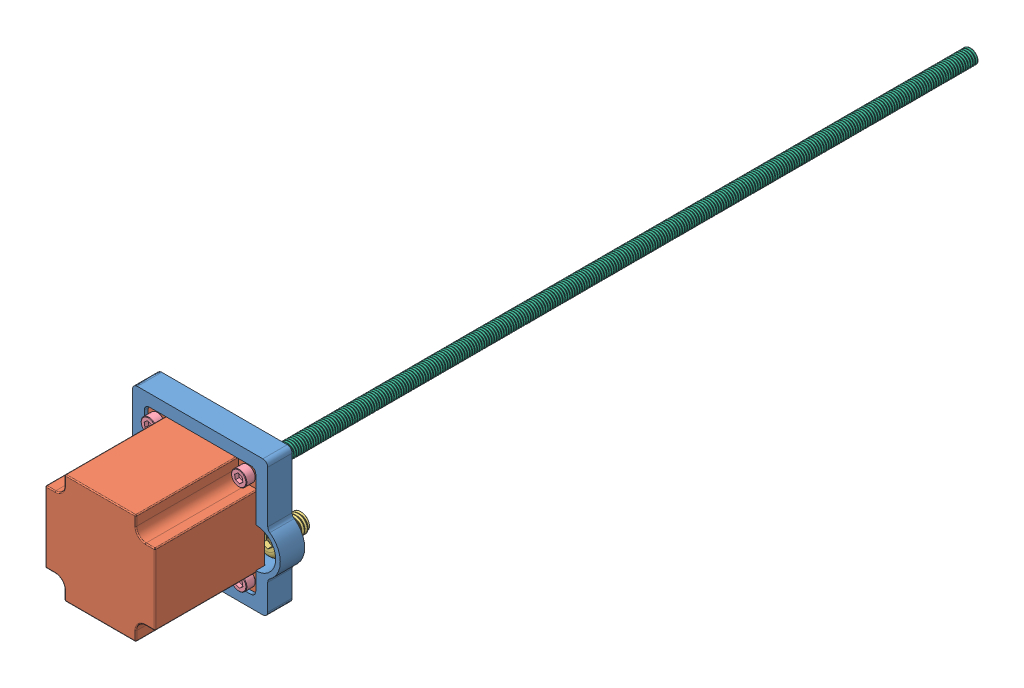
SolidWorks assembly motor_assembly, configuration Default. Lengths in mm.
Overall size (83.4 70.35 453.6).
10 component instances, 6 part files, 15 mates.
Components (placement in the parent):
- motor_mount-2: motor_mount [Default] at (-13.5344 2.352 77.0996) size (83.4 70.35 12.7)
- nema23-1: nema23 [Default] at (-13.5344 2.352 84.7196) size (57 57 78)
- S-375-050-BTN-H-SS-1: S-375-050-BTN-H-SS [Default] at (15.4656 -4.356 79.0554) size (16.66 16.66 18.24)
- S-010-716-SKT-H-SS-1: S-010-716-SKT-H-SS [Default] at (-37.0344 25.852 88.3796) x (1 0 0) z (0 -1 0) size (7.92 16.34 7.92)
- S-010-716-SKT-H-SS-2: S-010-716-SKT-H-SS [Default] at (-37.0344 -21.148 88.3796) x (1 0 0) z (0 -1 0) size (7.92 16.34 7.92)
- S-010-716-SKT-H-SS-3: S-010-716-SKT-H-SS [Default] at (9.9656 25.852 88.3796) x (1 0 0) z (0 -1 0) size (7.92 16.34 7.92)
- S-010-716-SKT-H-SS-4: S-010-716-SKT-H-SS [Default] at (9.9656 -21.148 88.3796) x (1 0 0) z (0 -1 0) size (7.92 16.34 7.92)
- S-375-050-BTN-H-SS-5: S-375-050-BTN-H-SS [Default] at (-42.5344 -4.356 79.0554) size (16.66 16.66 18.24)
- flex_joint-1: flex_joint [9861T431] at (-13.5344 2.352 73.3406) size (20.03 19.63 26.47)
- threaded_rod-1: threaded_rod [Default] at (-13.5344 2.352 -310.9304) x (1 0 0) z (0 -1 0) size (7.72 375.6 8.92)
Mates (geometry in assembly coordinates):
- Concentric1: concentric anti-aligned: circle of motor_mount-2; circle of nema23-1
- Concentric2: concentric aligned: circle of motor_mount-2; circle of nema23-1
- Coincident2: coincident anti-aligned: plane of motor_mount-2 through (-13.5344 2.352 84.7196) normal (0 0 1); plane of nema23-1 through (-13.5344 2.352 84.7196) normal (0 0 -1)
- Concentric4: concentric anti-aligned: circle of nema23-1; circle of S-010-716-SKT-H-SS-1
- Coincident4: coincident anti-aligned: plane of nema23-1 through (-37.0344 25.852 88.3796) normal (0 0 1); plane of S-010-716-SKT-H-SS-1 through (-37.0344 25.852 88.3796) normal (0 0 -1)
- Coincident5: coincident anti-aligned: plane of motor_mount-2 through (-37.4903 -4.356 79.0554) normal (0 0 1); plane of ? through (-42.5322 -4.356 79.0554) normal (0 0 -1)
- Concentric5: concentric anti-aligned: circle of motor_mount-2; circle of ?
- Concentric6: concentric anti-aligned: circle of motor_mount-2; circle of S-375-050-BTN-H-SS-1
- Coincident6: coincident anti-aligned: plane of motor_mount-2 through (20.5075 -4.356 79.0554) normal (0 0 1); plane of S-375-050-BTN-H-SS-1 through (15.4656 -4.356 79.0554) normal (0 0 -1)
- Coincident7: coincident anti-aligned: plane of motor_mount-2 through (-37.4925 -4.356 79.0554) normal (0 0 1); plane of S-375-050-BTN-H-SS-5 through (-42.5344 -4.356 79.0554) normal (0 0 -1)
- Concentric7: concentric anti-aligned: circle of motor_mount-2; circle of S-375-050-BTN-H-SS-5
- Concentric8: concentric aligned: circle of nema23-1; circle of flex_joint-1
- Distance1: distance = 0.254 mm anti-aligned: plane of nema23-1 through (-13.5344 2.352 83.1196) normal (0 0 -1); plane of flex_joint-1 through (-13.5344 2.352 82.8656) normal (0 0 1)
- Concentric9: concentric aligned: circle of flex_joint-1; circle of threaded_rod-1
- Coincident8: coincident anti-aligned: plane of nema23-1 through (-13.5344 2.352 63.7196) normal (0 0 -1); plane of threaded_rod-1 through (-13.5344 2.352 63.7196) normal (0 0 1)
